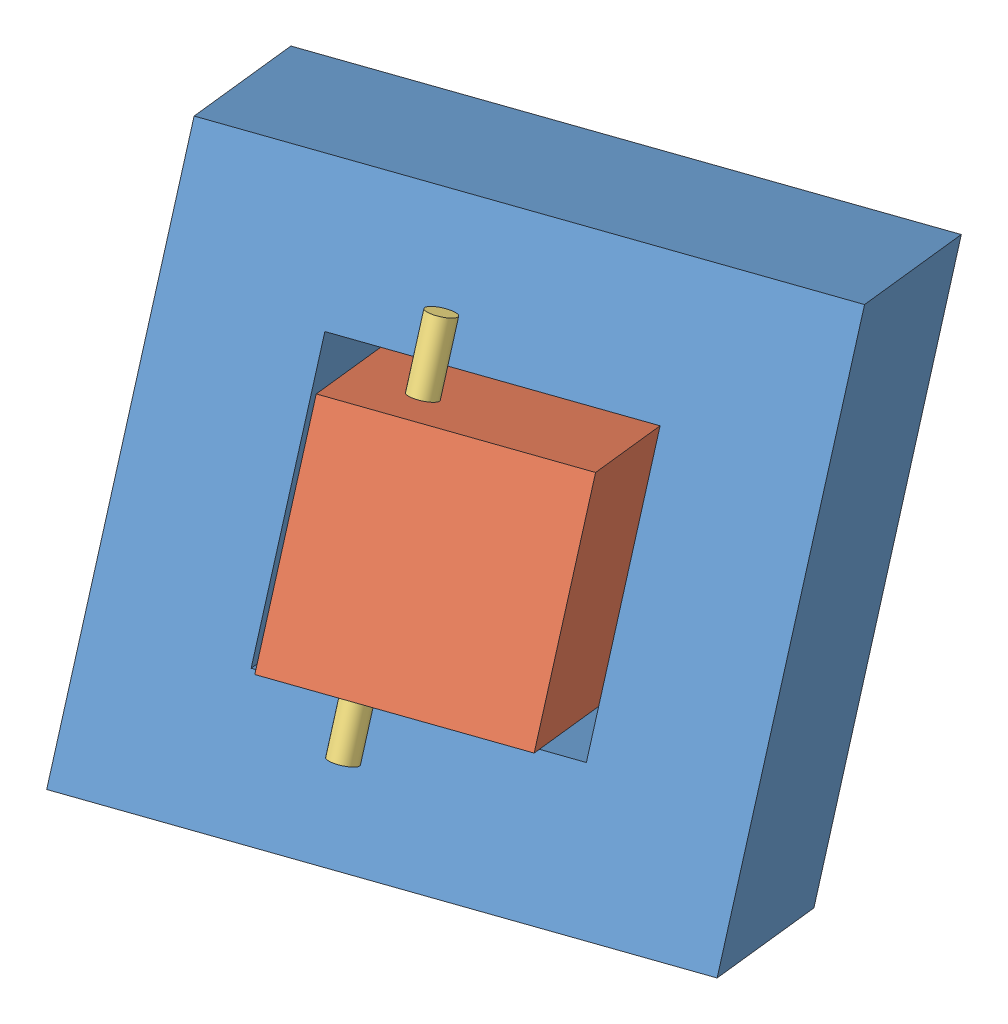
SolidWorks assembly cylinder symm, configuration Default. Lengths in mm.
Overall size (144.55 144.25 146.88).
4 component instances, 3 part files, 6 mates.
Components (placement in the parent):
- cubehole-1: cubehole [默认] at (33.7146 -62.7916 -81.8671) x (-0.897081 0.091332 0.432323) z (-0.432323 -0.383653 -0.816031) size (120 120 60)
- cube peg-2: cube peg [默认] at (12.9875 -85.3371 -121.5587) x (0.897081 -0.091332 -0.432323) z (0.432323 0.383653 0.816031) size (50 50 90)
- cylindersensor-1: cylindersensor [Default] at (33.0624 -96.6718 -42.2878) x (-0.73837 -0.320999 -0.593102) z (-0.091332 0.91895 -0.383653) size (6 6 15)
- cylindersensor-2: cylindersensor [Default] at (29.946 -22.2326 -71.7663) x (0.993971 0.060658 -0.091332) z (0.091332 -0.91895 0.383653) size (6 6 15)
Mates (geometry in assembly coordinates):
- 重合1: coincident anti-aligned: plane of cubehole-1 through (12.0984 -81.9742 -122.6687) normal (0.432323 0.383653 0.816031); plane of cube peg-2 through (12.9875 -85.3371 -121.5587) normal (-0.432323 -0.383653 -0.816031)
- 重合2: coincident anti-aligned: plane of cubehole-1 through (28.5982 -66.6067 -138.6351) normal (0.091332 -0.91895 0.383653); plane of cube peg-2 through (22.6532 -27.5113 -43.5761) normal (-0.091332 0.91895 -0.383653)
- 重合3: coincident anti-aligned: plane of cubehole-1 through (28.5982 -66.6067 -138.6351) normal (-0.897081 0.091332 0.432323); plane of cube peg-2 through (67.5073 -32.0779 -65.1923) normal (0.897081 -0.091332 -0.432323)
- 重合4: coincident anti-aligned: plane of cube peg-2 through (27.2199 -73.4588 -24.3934) normal (0.091332 -0.91895 0.383653); plane of cylindersensor-1 through (32.6356 -81.2526 -44.3511) normal (-0.091332 0.91895 -0.383653)
- 重合5: coincident anti-aligned: plane of cube peg-2 through (22.6532 -27.5113 -43.5761) normal (-0.091332 0.91895 -0.383653); plane of cylindersensor-2 through (28.0689 -35.3052 -63.5337) normal (0.091332 -0.91895 0.383653)
- 同心1: concentric anti-aligned: cylinder of cylindersensor-1 through (32.6356 -81.2526 -44.3511) axis (0.091332 -0.91895 0.383653) radius 3; cylinder of cylindersensor-2 through (28.0689 -35.3052 -63.5337) axis (-0.091332 0.91895 -0.383653) radius 3
